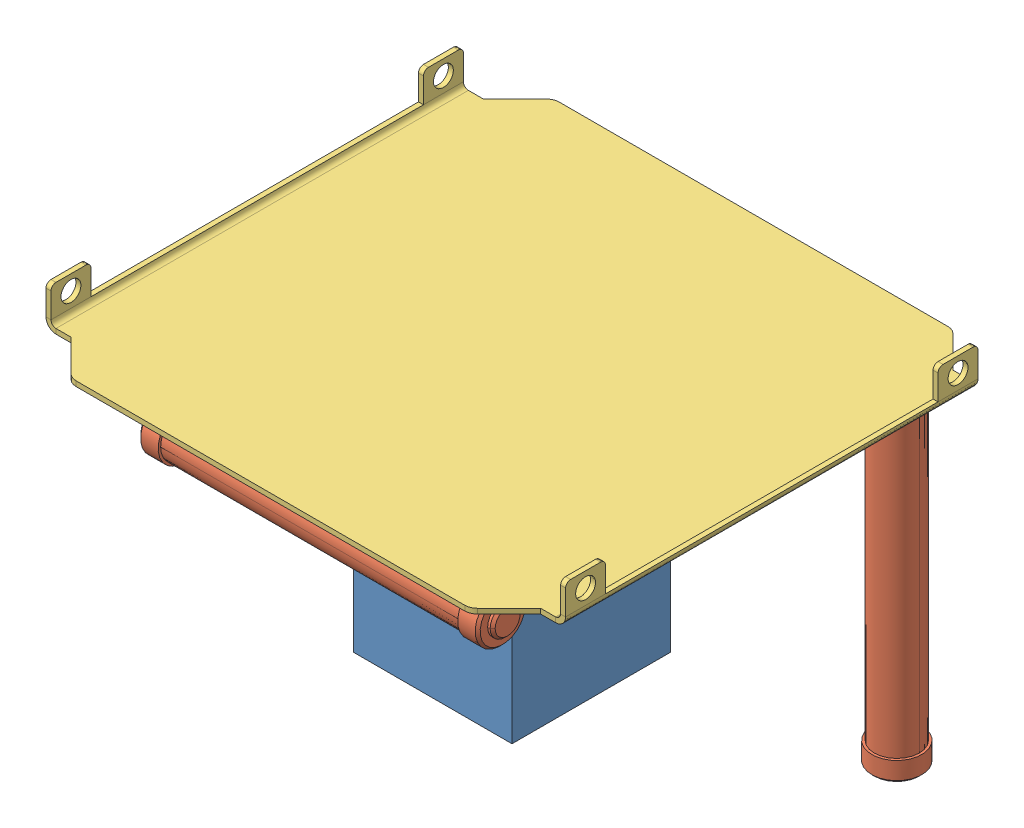
SolidWorks assembly Spirit2U - ADCS Shelf, configuration Default. Lengths in mm.
Overall size (104.07 78 96.74).
7 component instances, 5 part files, 22 mates.
Components (placement in the parent):
- PCM Heat Sink-1: PCM Heat Sink [Default] at (52.036 -1 -41.3) x (1 0 0) z (0 -1 0) size (31.75 31.75 31.75)
- NCTR-MAS-001-01.A - M002 Cubesat Torque Rod (Defeatured)-1: NCTR-MAS-001-01.A - M002 Cubesat Torque Rod (Defeatured) [Default] at (5 19.8958 7.686) x (0 0 1) z (1 0 0) size (70 10 10)
- NCTR-MAS-001-01.A - M002 Cubesat Torque Rod (Defeatured)-2: NCTR-MAS-001-01.A - M002 Cubesat Torque Rod (Defeatured) [Default] at (104.6869 -31.8589 -7.9289) size (70 10 10)
- Spirit2U Tranceiver Shelf 2-1: Spirit2U Tranceiver Shelf 2 [Default] at origin size (104.07 8 96.74)
- NCTR-MAS-001-01.A - M002 Cubesat Torque Rod (Defeatured)-3: NCTR-MAS-001-01.A - M002 Cubesat Torque Rod (Defeatured) [Default] at (84.072 11.6149 -104.6711) x (0 1 0) z (1 0 0) size (70 10 10)
- Gyroscope-2: Gyroscope [Default] at (95.922 -1 -68.4289) x (1 0 0) z (0 -1 0) size (6.3 5.5 2.63)
- Magnetometer-3: Magnetometer [Default] at (95.072 -2 -52.9289) size (2 1 2)
Mates (geometry in assembly coordinates):
- Coincident177: coincident: plane of PCM Heat Sink-1 through (52.036 -1 -41.3) normal (0 1 0); plane of Spirit2U Tranceiver Shelf 2-1 through (0 -1 0) normal (0 -1 0)
- Distance18: distance = 12 mm: plane of NCTR-MAS-001-01.A - M002 Cubesat Torque Rod (Defeatured)-1 through (12.545 -5.9815 -4.9289) normal (0 0 1); plane of Spirit2U Tranceiver Shelf 2-1 through (12.0711 -1 7.0711) normal (0 0 1)
- Distance20: distance = 5 mm: plane of NCTR-MAS-001-01.A - M002 Cubesat Torque Rod (Defeatured)-1 through (5 19.8958 7.686) normal (1 0 0); plane of Spirit2U Tranceiver Shelf 2-1 through (0 0 0) normal (-1 0 0)
- Distance16: distance = 12 mm: plane of NCTR-MAS-001-01.A - M002 Cubesat Torque Rod (Defeatured)-2 through (92.072 -5.9815 -0.3839) normal (1 0 0); plane of Spirit2U Tranceiver Shelf 2-1 through (104.072 0 0) normal (1 0 0)
- Coincident176: coincident: plane of Spirit2U Tranceiver Shelf 2-1 through (0 -1 0) normal (0 -1 0); plane of NCTR-MAS-001-01.A - M002 Cubesat Torque Rod (Defeatured)-3 through (91.617 -1 -78.7937) normal (0 1 0)
- Distance21: distance = 20 mm: plane of NCTR-MAS-001-01.A - M002 Cubesat Torque Rod (Defeatured)-3 through (84.072 11.6149 -104.6711) normal (1 0 0); plane of Spirit2U Tranceiver Shelf 2-1 through (104.072 0 0) normal (1 0 0)
- Distance22: distance = 15 mm: plane of NCTR-MAS-001-01.A - M002 Cubesat Torque Rod (Defeatured)-3 through (84.072 11.6149 -104.6711) normal (0 0 1); plane of Spirit2U Tranceiver Shelf 2-1 through (92.0009 -1 -89.6711) normal (0 0 -1)
- Coincident178: coordinate: point of Spirit2U Tranceiver Shelf 2-1; point of assembly
- Coincident179: coincident: line of NCTR-MAS-001-01.A - M002 Cubesat Torque Rod (Defeatured)-1 through (12.9742 -1 -6.4289) axis (0 0 -1); plane of Spirit2U Tranceiver Shelf 2-1 through (0 -1 0) normal (0 -1 0)
- Coincident180: coincident: line of NCTR-MAS-001-01.A - M002 Cubesat Torque Rod (Defeatured)-2 through (90.572 -1 -0.8131) axis (-1 0 0); plane of Spirit2U Tranceiver Shelf 2-1 through (0 -1 0) normal (0 -1 0)
- Distance23: distance = 15 mm: plane of NCTR-MAS-001-01.A - M002 Cubesat Torque Rod (Defeatured)-2 through (104.6869 -31.8589 -7.9289) normal (0 0 1); plane of Spirit2U Tranceiver Shelf 2-1 through (12.0711 -1 7.0711) normal (0 0 1)
- Coincident182: coincident: plane of PCM Heat Sink-1 through (52.036 -1 -41.3) normal (0 0 1); plane of assembly through (0 0 -41.3) normal (0 0 1)
- Coincident183: coincident: plane of PCM Heat Sink-1 through (52.036 -1 -41.3) normal (1 0 0); plane of assembly through (52.036 0 0) normal (1 0 0)
- Coincident184: coincident: plane of Spirit2U Tranceiver Shelf 2-1 through (0 -1 0) normal (0 -1 0); point of Gyroscope-2
- Coincident185: coincident: plane of Spirit2U Tranceiver Shelf 2-1 through (0 -1 0) normal (0 -1 0); point of Gyroscope-2
- Coincident186: coincident: plane of Spirit2U Tranceiver Shelf 2-1 through (0 -1 0) normal (0 -1 0); point of Gyroscope-2
- Distance24: distance = 5 mm: plane of Spirit2U Tranceiver Shelf 2-1 through (104.072 0 0) normal (1 0 0); point of Gyroscope-2
- Distance25: distance = 5 mm: plane of Spirit2U Tranceiver Shelf 2-1 through (104.072 0 0) normal (1 0 0); point of Gyroscope-2
- Distance26: distance = 70 mm: point of Gyroscope-2; plane of Spirit2U Tranceiver Shelf 2-1 through (12.0711 -1 7.0711) normal (0 0 1)
- Coincident189: coincident: plane of Spirit2U Tranceiver Shelf 2-1 through (0 -1 0) normal (0 -1 0); plane of Magnetometer-3 through (95.072 -1 -52.9289) normal (0 1 0)
- Distance27: distance = 7 mm: plane of Spirit2U Tranceiver Shelf 2-1 through (104.072 0 0) normal (1 0 0); plane of Magnetometer-3 through (97.072 -1 -52.9289) normal (1 0 0)
- Distance28: distance = 60 mm: plane of Magnetometer-3 through (95.072 -1 -52.9289) normal (0 0 1); plane of Spirit2U Tranceiver Shelf 2-1 through (12.0711 -1 7.0711) normal (0 0 1)
